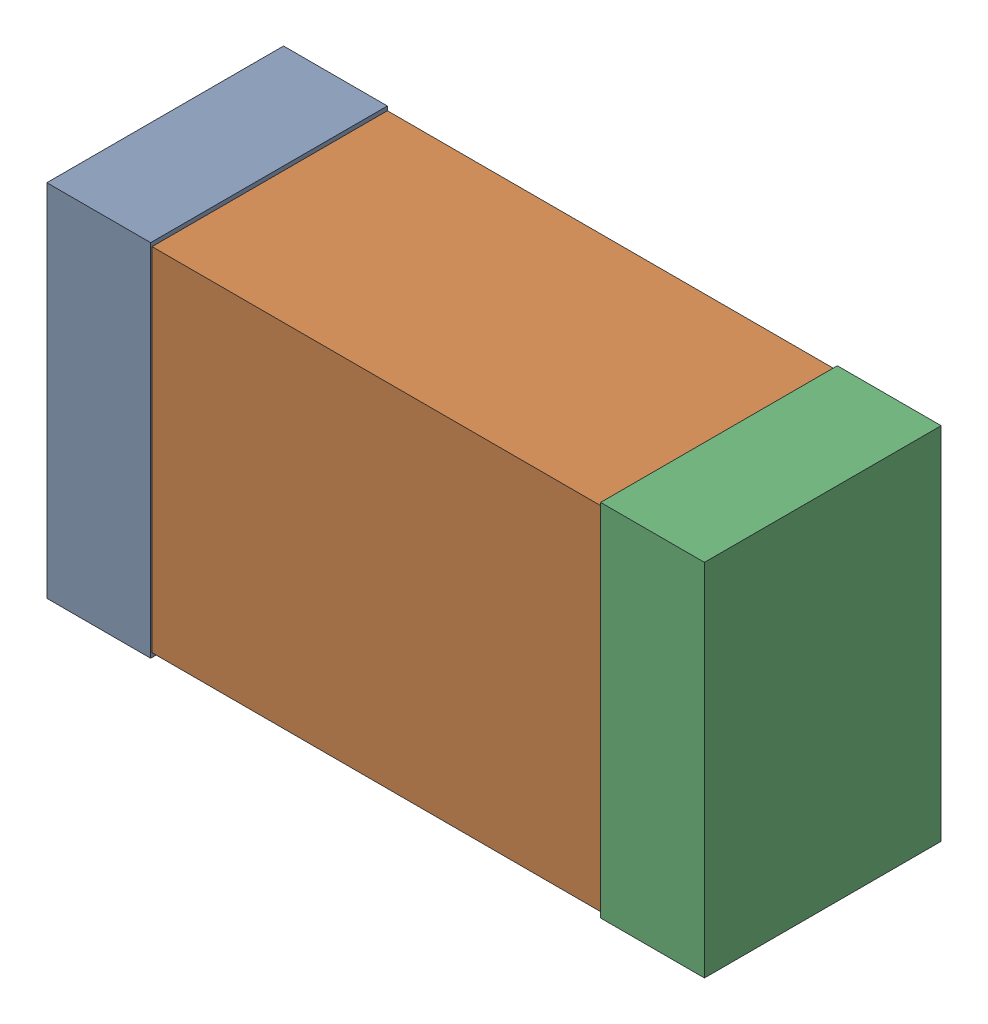
SolidWorks assembly R3_Motor_7Kanaloa_v2.0.0_Motor, configuration Default. Lengths in mm.
Overall size (2.38 1.3 0.85).
6 component instances, 2 part files, 0 mates.
Components (placement in the parent):
- 352877648-1: 352877648 [Default] at (84.28 147.574 0) size (0.38 1.3 0.85)
  - Extruded_14-1: Extruded_14 [Default] at origin size (0.38 1.3 0.85)
- 352877392-1: 352877392 [Default] at (85.28 147.574 0) size (2.2 1.27 0.85)
  - Extruded_15-1: Extruded_15 [Default] at origin size (2.2 1.27 0.85)
- 352877648-2: 352877648 [Default] at (86.28 147.574 0) size (0.38 1.3 0.85)
  - Extruded_14-1: Extruded_14 [Default] at origin size (0.38 1.3 0.85)
